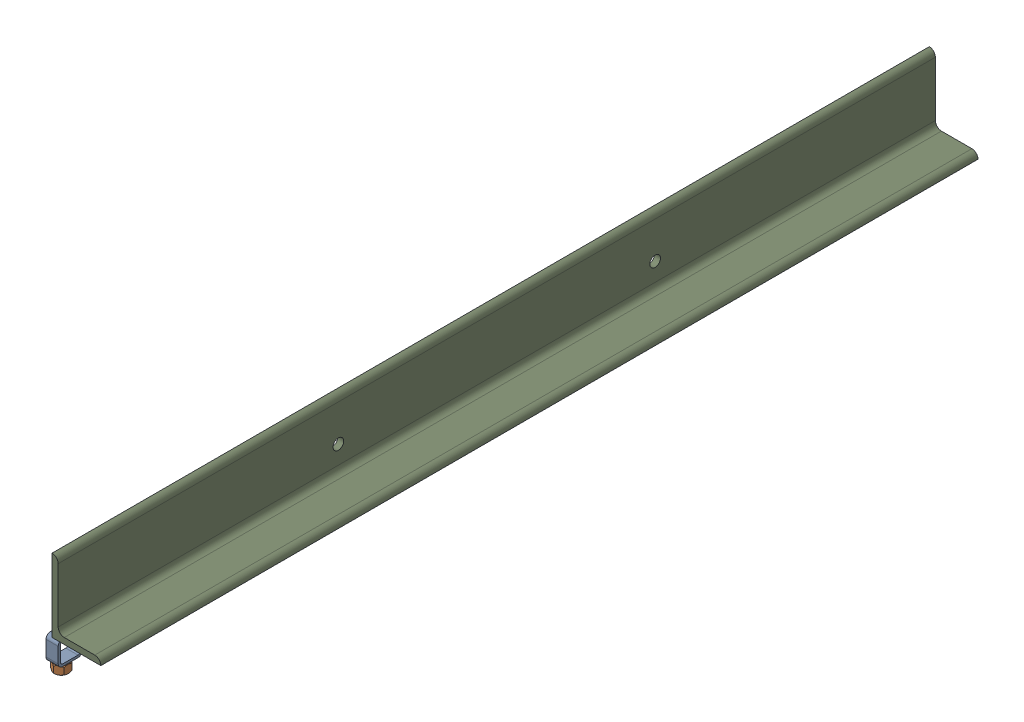
SolidWorks assembly 01-018-00-0, configuration Default. Lengths in mm.
Overall size (177.8 220.09 1828.8).
17 component instances, 4 part files, 0 mates.
Components (placement in the parent):
- 01-003-00-0-1-1: 01-003-00-0-1 [Default] at origin size (115.89 220.09 1828.8)
  - 01-005-00-0-10-1: 01-005-00-0-10 [Default] at (-6.35 0 863.6) x (0 -1 0) z (-1 0 0) size (67.69 50.8 28.57)
    - tube square_ai(PreviewCfg)-1: tube square_ai(PreviewCfg) [Default] at origin size (50.8 50.8 25.4)
    - hex nut_ai(HNUT 0.7500-10-D-C)-1: hex nut_ai(HNUT 0.7500-10-D-C) [Default] at (67.691 31.75 0) x (0 0 -1) z (1 0 0) size (28.57 33 16.89)
  - 01-005-00-0-11-1: 01-005-00-0-11 [Default] at (-6.35 0 -914.4) x (0 -1 0) z (-1 0 0) size (67.69 50.8 28.57)
    - tube square_ai(PreviewCfg)-1: tube square_ai(PreviewCfg) [Default] at origin size (50.8 50.8 25.4)
    - hex nut_ai(HNUT 0.7500-10-D-C)-1: hex nut_ai(HNUT 0.7500-10-D-C) [Default] at (67.691 31.75 0) x (0 0 -1) z (1 0 0) size (28.57 33 16.89)
  - 01-005-00-0-12-1: 01-005-00-0-12 [Default] at (-6.35 0 -609.6) x (0 -1 0) z (-1 0 0) size (67.69 50.8 28.57)
    - tube square_ai(PreviewCfg)-1: tube square_ai(PreviewCfg) [Default] at origin size (50.8 50.8 25.4)
    - hex nut_ai(HNUT 0.7500-10-D-C)-1: hex nut_ai(HNUT 0.7500-10-D-C) [Default] at (67.691 31.75 0) x (0 0 -1) z (1 0 0) size (28.57 33 16.89)
  - 01-005-00-0-13-1: 01-005-00-0-13 [Default] at (-6.35 0 558.8) x (0 -1 0) z (-1 0 0) size (67.69 50.8 28.57)
    - tube square_ai(PreviewCfg)-1: tube square_ai(PreviewCfg) [Default] at origin size (50.8 50.8 25.4)
    - hex nut_ai(HNUT 0.7500-10-D-C)-1: hex nut_ai(HNUT 0.7500-10-D-C) [Default] at (67.691 31.75 0) x (0 0 -1) z (1 0 0) size (28.57 33 16.89)
  - 01-004-00-0-1: 01-004-00-0 [Default] at (-6.35 0 0) size (101.6 152.4 1828.8)
- 01-017-00-0-1: 01-017-00-0 [Default] at (-82.55 76.2 -36.35) x (1 0 0) z (0 1 0) size (76.2 12.7 76.2)
- 01-017-00-0-2: 01-017-00-0 [Default] at (-82.55 76.2 6.35) x (1 0 0) z (0 1 0) size (76.2 12.7 76.2)
- 01-017-00-0-3: 01-017-00-0 [Default] at (-82.55 0 36.35) x (1 0 0) z (0 -1 0) size (76.2 12.7 76.2)
